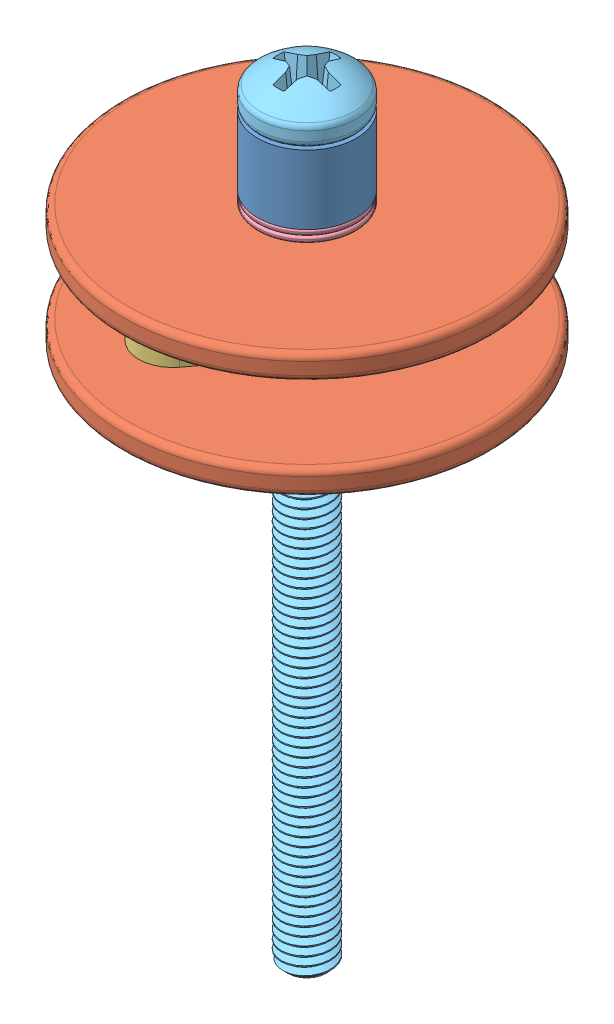
SolidWorks assembly spindle_sub_assembly, configuration Default. Lengths in mm.
Overall size (37.67 65.55 37.67).
8 component instances, 5 part files, 14 mates.
Components (placement in the parent):
- spindle_shaft-1: spindle_shaft [Default] at (9.1523 -6.9167 29.8135) size (8 5.6 8)
- top_ring-1: top_ring [Default] at (4.3402 31.9804 168.7359) x (0.991452 0.000169 -0.130469) z (0.000177 -1 0.000051) size (30 30 2.01)
- top_ring-2: top_ring [Default] at (-10.4741 23.8804 -107.7998) x (-0.953205 0.000169 0.302326) z (-0.000183 -1 -0.000019) size (30 30 2.01)
- oval_slider-1: oval_slider [Default] at (9.1523 -10.4167 29.8135) x (0.496424 0 -0.86808) z (-0.86808 0 -0.496424) size (21.5 5.6 6.52)
- 4_8_shim-4: 4_8_shim [Default] at (9.1523 -10.4167 29.8135) size (8 0.5 8)
- 4_8_shim-5: 4_8_shim [Default] at (9.1523 -7.9167 29.8135) size (8 0.5 8)
- 4_8_shim-6: 4_8_shim [Default] at (9.1523 -7.4167 29.8135) size (8 0.5 8)
- m4_60mm-1: m4_60mm [92000A248] at (9.1523 -61.3167 29.8135) x (1 0 0) z (0 1 0) size (8 8 65.55)
Mates (geometry in assembly coordinates):
- Concentric15: concentric aligned: circle of top_ring-1; cylinder of 4_8_shim-4 through (9.1523 -9.9167 29.8135) axis (0 -1 0) radius 2
- Coincident16: coincident anti-aligned: plane of top_ring-1 through (9.1523 -9.9167 29.8135) normal (0 -1 0); circle of 4_8_shim-4
- Concentric16: concentric anti-aligned: cylinder of oval_slider-1 through (9.1523 -16.0167 29.8135) axis (0 1 0) radius 1.9114; circle of 4_8_shim-4
- Coincident22: coincident anti-aligned: plane of spindle_shaft-1 through (9.1523 -6.9167 29.8135) normal (0 -1 0); plane of 4_8_shim-6 through (9.1523 -6.9167 29.8135) normal (0 1 0)
- Coincident23: coincident anti-aligned: plane of 4_8_shim-5 through (9.1523 -7.4167 29.8135) normal (0 1 0); plane of 4_8_shim-6 through (9.1523 -7.4167 29.8135) normal (0 -1 0)
- Coincident24: coincident anti-aligned: plane of top_ring-1 through (9.1523 -7.9167 29.8135) normal (0 1 0); plane of 4_8_shim-5 through (9.1523 -7.9167 29.8135) normal (0 -1 0)
- Concentric17: concentric anti-aligned: cylinder of spindle_shaft-1 through (9.1523 -1.3167 29.8135) axis (0 -1 0) radius 2; circle of m4_60mm-1
- Coincident25: coincident anti-aligned: plane of spindle_shaft-1 through (9.1523 -1.3167 29.8135) normal (0 1 0); plane of m4_60mm-1 through (9.1523 -1.3167 29.8135) normal (0 -1 0)
- Coincident27: coincident anti-aligned: plane of top_ring-2 through (9.1523 -16.0167 29.8135) normal (0 1 0); plane of oval_slider-1 through (5.1809 -16.0167 36.7581) normal (0 -1 0)
- Coincident28: coincident anti-aligned: plane of oval_slider-1 through (5.1809 -10.4167 36.7581) normal (0 1 0); plane of 4_8_shim-4 through (9.1523 -10.4167 29.8135) normal (0 -1 0)
- Concentric18: concentric aligned: circle of top_ring-2; cylinder of oval_slider-1 through (9.1523 -16.0167 29.8135) axis (0 1 0) radius 1.9114
- Concentric19: concentric aligned: cylinder of top_ring-1 through (9.1523 -7.9167 29.8135) axis (0 -1 0) radius 1.5; cylinder of 4_8_shim-5 through (9.1523 -7.4167 29.8135) axis (0 -1 0) radius 2
- Concentric20: concentric aligned: cylinder of 4_8_shim-5 through (9.1523 -7.4167 29.8135) axis (0 -1 0) radius 2; cylinder of 4_8_shim-6 through (9.1523 -6.9167 29.8135) axis (0 -1 0) radius 2
- Concentric21: concentric aligned: cylinder of spindle_shaft-1 through (9.1523 -1.3167 29.8135) axis (0 -1 0) radius 2; cylinder of 4_8_shim-6 through (9.1523 -6.9167 29.8135) axis (0 -1 0) radius 2
